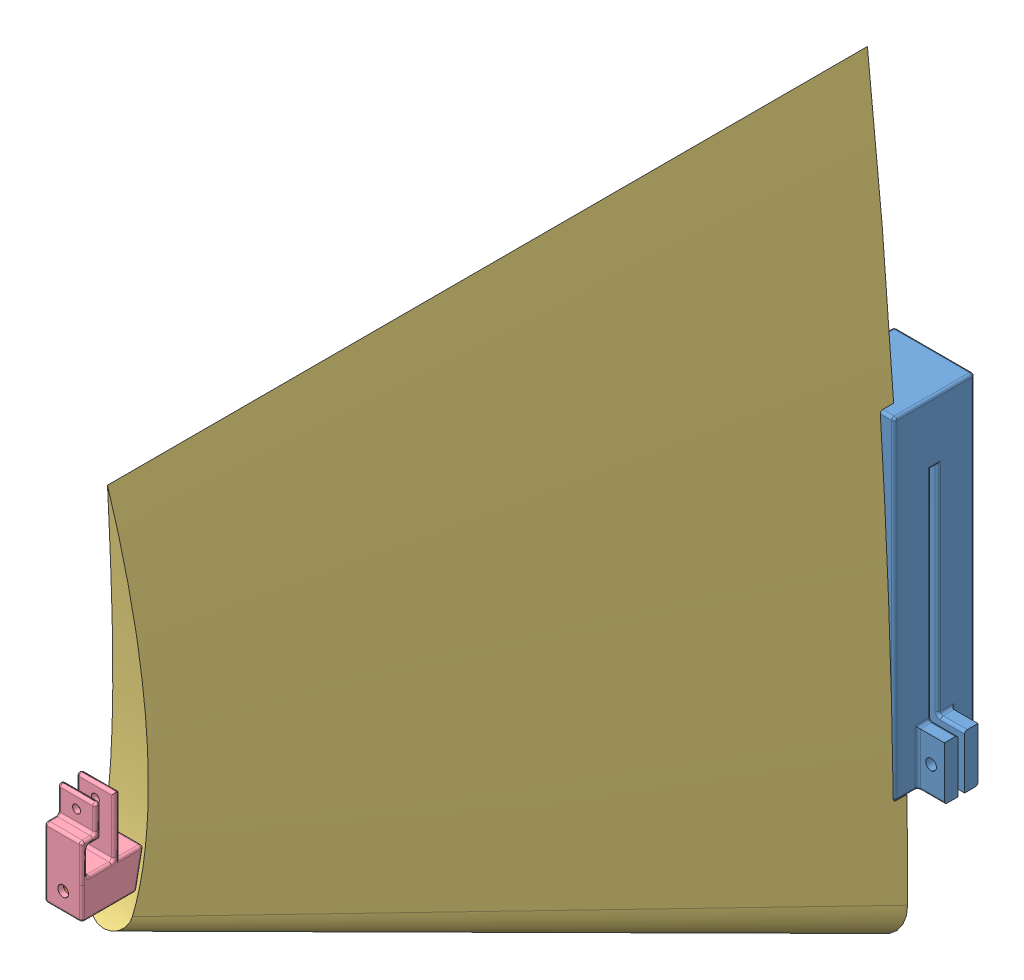
SolidWorks assembly vertical stabiliser, configuration Default. Lengths in mm.
Overall size (372.03 337.13 325.08).
23 component instances, 17 part files, 65 mates.
Components (placement in the parent):
- Tail Boom-1: Tail Boom [Default] at (20.2266 -517.2222 1.0272) size (20 1000 20) (hidden)
- Tail holder 1-1: Tail holder 1 [Default] at (31.2437 406.7778 -2.2179) x (1 0 0) z (0 -1 0) size (40 30 124) (hidden)
- tail holder 2-2: tail holder 2 [Default] at (21.0079 496.8403 300.9572) x (0 1 0) z (-1 0 0) size (10 323.08 10) (hidden)
- Tail Boom-2: Tail Boom [Default] at (-93.7734 -517.2222 1.0272) x (-1 0 0) z (0 0 -1) size (20 1000 20) (hidden)
- Tail holder 1-3: Tail holder 1 [Default] at (-104.7904 406.7778 4.2723) x (-1 0 0) z (0 -1 0) size (40 30 124)
- Vertical Stabilizer mk1-1: Vertical Stabilizer mk1 [Default] at (20.2266 346.1726 11.0272) x (-1 0 0) z (0 0 1) size (32.74 289.69 300.05) (hidden)
- tail holder 2-3: tail holder 2 [Default] at (-90.2109 492.4966 300.9572) x (1 0 0) z (0 1 0) size (10 323.08 10)
- Vertical Stabilizer mk1-2: Vertical Stabilizer mk1 [Default] at (-93.7734 346.1726 11.0272) x (-1 0 0) z (0 0 1) size (32.74 289.69 300.05)
- Horisontal stabiliser 11-1: Horisontal stabiliser 11 [Default] at (-336.7734 468.2778 304.1044) x (0 1 0) z (1 0 0) size (201.07 42.21 600) (hidden)
- top tail holder-1: top tail holder [Default] at (-94.9301 489.7185 257.1044) x (0 -1 0) z (-1 0 0) size (36 23 14)
- top tail holder-3: top tail holder [Default] at (19.0699 489.7185 257.1044) x (0 -1 0) z (-1 0 0) size (36 23 14) (hidden)
- Horizontal stabilizer bar-1: Horizontal stabilizer bar [Default] at (-336.7734 503.5632 301.2248) x (0 0 -1) z (1 0 0) size (10 10 600) (hidden)
- Tail motor mount A mk1-1: Tail motor mount A mk1 [Default] at (-97.9309 255.7778 2.925) x (1 0 0) z (0 -1 0) size (55 30 50) (hidden)
- Tail motor mount A mk1-2: Tail motor mount A mk1 [Default] at (24.3842 255.7778 -0.8707) x (-1 0 0) z (0 -1 0) size (55 30 50) (hidden)
- Rear motor crossbar-1: Rear motor crossbar [Default] at (-83.7734 228.9438 2.5044) x (0 1 0) z (1 0 0) size (20 20 94) (hidden)
- Tail motor mount B mk1-1: Tail motor mount B mk1 [Default] at (-38.3549 230.7778 31.0272) x (-1 0 0) z (0 -1 0) size (24 47 40) (hidden)
- Servo mk1-1: Servo mk1 [Default] at (-101.0589 247.0979 -13.9728) x (0.971449 -0.237248 0) z (0.237248 0.971449 0) size (33.6 12.5 34.08) (hidden)
- Flap mk1-1: Flap mk1 [Default] at (-35.9741 313.2778 -18.4266) x (0.996557 0 -0.082916) z (0 -1 0) size (2 40 165) (hidden)
- Servo arm mk1-1: Servo arm mk1 [Default] at (-114.6733 232.8778 17.976) x (-0.995872 0 0.090763) z (0 -1 0) size (10.8 29.4 3.1) (hidden)
- Servo hook mk1-1: Servo hook mk1 [Default] at (-40.7562 235.7778 -42.4932) x (-0.996557 0 0.082916) z (0.082916 0 0.996557) size (6 10 10) (hidden)
- Servo wire-1: Servo wire [Default] at (-102.5419 227.3778 -25.7684) x (-0.039777 0 0.999209) z (0 1 0) size (2 59.28 13) (hidden)
- Tail motor-1: Tail motor [Default] at (-36.7734 230.7778 31.0272) x (-0.55385 -0.832617 0) z (0 0 -1) size (27.5 27.5 31.35) (hidden)
- tail prop-1: tail prop [Default] at (-36.7734 230.7778 54.3772) x (0.926424 -0.376482 0) z (-0.376482 -0.926424 0) size (111.23 11.43 97.73) (hidden)
Mates (geometry in assembly coordinates):
- Distance4: distance = 94 mm anti-aligned: plane of Tail Boom-1 through (10.2266 482.7778 10.0272) normal (-1 0 0); plane of Tail Boom-2 through (-83.7734 482.7778 -7.9728) normal (1 0 0)
- Coincident27: coincident aligned: plane of Tail Boom-1 through (11.2266 482.7778 -8.9728) normal (0 0 -1); plane of Tail Boom-2 through (-84.7734 482.7778 -8.9728) normal (0 0 -1)
- Coincident59: coincident anti-aligned: plane of Tail Boom-2 through (-84.7734 482.7778 -8.9728) normal (0 0 -1); plane of Tail holder 1-3 through (-104.7904 381.7778 -8.9728) normal (0 0 1)
- Coincident60: coincident anti-aligned: plane of Tail Boom-2 through (-103.7734 482.7778 -7.9728) normal (-1 0 0); plane of Tail holder 1-3 through (-103.7734 381.7778 4.2723) normal (1 0 0)
- Parallel1: parallel anti-aligned: plane of Tail Boom-2 through (-83.7734 482.7778 -7.9728) normal (1 0 0); plane of Tail holder 1-3 through (-83.7734 381.7778 4.2723) normal (-1 0 0)
- Coincident63: coincident anti-aligned: plane of Tail Boom-2 through (-84.7734 482.7778 -7.9728) normal (0 1 0); plane of Tail holder 1-3 through (-104.7904 482.7778 4.2723) normal (0 -1 0)
- Coincident64: coincident anti-aligned: plane of Tail Boom-1 through (11.2266 482.7778 10.0272) normal (0 1 0); plane of Tail holder 1-1 through (31.2437 482.7778 -2.2179) normal (0 -1 0)
- Coincident65: coincident anti-aligned: plane of Tail Boom-1 through (10.2266 482.7778 10.0272) normal (-1 0 0); plane of Tail holder 1-1 through (10.2266 381.7778 -2.2179) normal (1 0 0)
- Coincident66: coincident anti-aligned: plane of Tail Boom-1 through (11.2266 482.7778 11.0272) normal (0 0 1); plane of Tail holder 1-1 through (31.2437 381.7778 11.0272) normal (0 0 -1)
- Coincident67: coincident anti-aligned: plane of Tail holder 1-1 through (31.2437 498.2778 110.0272) normal (0 -1 0); plane of tail holder 2-2 through (25.2266 498.2778 -9.0428) normal (0 1 0)
- Coincident68: coincident aligned: plane of Tail holder 1-1 through (31.2437 381.7778 -13.9728) normal (0 0 -1); plane of tail holder 2-2 through (16.2266 489.2778 -13.9728) normal (0 0 -1)
- Coincident69: coincident anti-aligned: plane of Tail holder 1-1 through (15.2266 406.7778 110.0272) normal (1 0 0); plane of tail holder 2-2 through (15.2266 488.2778 -9.0428) normal (-1 0 0)
- Coincident71: coincident aligned: plane of Tail holder 1-3 through (-104.7904 381.7778 -13.9728) normal (0 0 -1); plane of tail holder 2-3 through (-97.7734 497.2778 -13.9728) normal (0 0 -1)
- Coincident72: coincident anti-aligned: plane of Tail holder 1-3 through (-88.7734 406.7778 -107.9728) normal (-1 0 0); plane of tail holder 2-3 through (-88.7734 488.2778 -9.0428) normal (1 0 0)
- Coincident73: coincident anti-aligned: plane of Horisontal stabiliser 11-1 through (-336.7734 486.2778 267.1044) normal (0 1 0); plane of top tail holder-3 through (27.2266 486.2778 297.1044) normal (0 -1 0)
- Coincident74: coincident anti-aligned: plane of Horisontal stabiliser 11-1 through (27.2266 468.2778 267.1044) normal (-1 0 0); plane of top tail holder-3 through (27.2266 500.2778 297.1044) normal (1 0 0)
- Coincident75: coincident anti-aligned: plane of Horisontal stabiliser 11-1 through (-336.7734 468.2778 311.1044) normal (0 0 -1); plane of top tail holder-3 through (19.0699 489.7185 311.1044) normal (0 0 1)
- Coincident76: coincident anti-aligned: plane of Horisontal stabiliser 11-1 through (-100.7734 468.2778 267.1044) normal (1 0 0); plane of top tail holder-1 through (-100.7734 500.2778 297.1044) normal (-1 0 0)
- Coincident77: coincident anti-aligned: plane of Horisontal stabiliser 11-1 through (-336.7734 486.2778 267.1044) normal (0 1 0); plane of top tail holder-1 through (-86.7734 486.2778 297.1044) normal (0 -1 0)
- Coincident78: coincident anti-aligned: plane of Horisontal stabiliser 11-1 through (-336.7734 468.2778 311.1044) normal (0 0 -1); plane of top tail holder-1 through (-94.9301 489.7185 311.1044) normal (0 0 1)
- Coincident81: coincident anti-aligned: plane of Horisontal stabiliser 11-1 through (-390.7734 500.2778 304.1044) normal (0 1 0); plane of Horizontal stabilizer bar-1 through (263.2266 500.2778 309.1044) normal (0 -1 0)
- Coincident83: coincident anti-aligned: plane of Horisontal stabiliser 11-1 through (-390.7734 468.2778 309.1044) normal (0 0 -1); plane of Horizontal stabilizer bar-1 through (263.2266 510.2778 309.1044) normal (0 0 1)
- Coincident84: coincident aligned: plane of Horisontal stabiliser 11-1 through (263.2266 468.2778 304.1044) normal (1 0 0); plane of Horizontal stabilizer bar-1 through (263.2266 503.5632 301.2248) normal (1 0 0)
- Coincident86: coincident anti-aligned: plane of tail holder 2-3 through (-88.7734 488.2778 -9.0428) normal (1 0 0); plane of Vertical Stabilizer mk1-2 through (-88.7734 346.1726 321.0272) normal (-1 0 0)
- Coincident87: coincident anti-aligned: plane of tail holder 2-3 through (-98.7734 488.2778 -9.0428) normal (0 -1 0); plane of Vertical Stabilizer mk1-2 through (-93.7734 488.2778 321.0272) normal (0 1 0)
- Coincident89: coincident anti-aligned: plane of tail holder 2-2 through (25.2266 488.2778 -9.0428) normal (0 -1 0); plane of Vertical stabiliser 11-1 through (20.2266 488.2778 321.0272) normal (0 1 0)
- Coincident90: coincident anti-aligned: plane of tail holder 2-2 through (15.2266 488.2778 -9.0428) normal (-1 0 0); plane of Vertical stabiliser 11-1 through (15.2266 346.1726 321.0272) normal (1 0 0)
- Coincident91: coincident anti-aligned: plane of tail holder 2-2 through (25.2266 488.2778 -9.0428) normal (1 0 0); plane of top tail holder-3 through (25.2266 489.7185 257.1044) normal (-1 0 0)
- Coincident92: coincident anti-aligned: plane of tail holder 2-2 through (25.2266 488.2778 -9.0428) normal (0 -1 0); plane of top tail holder-3 through (19.0699 488.2778 257.1044) normal (0 1 0)
- Distance5: distance = 311.0772 mm: line of top tail holder-1 through (-87.7734 500.2778 297.1044) axis (-1 0 0); plane of tail holder 2-3 through (-97.7734 497.2778 -13.9728) normal (0 0 -1)
- Coincident93: coincident anti-aligned: plane of Tail Boom-1 through (11.2266 482.7778 11.0272) normal (0 0 1); plane of Vertical stabiliser 11-1 through (20.2266 346.1726 11.0272) normal (0 0 -1)
- Coincident94: coincident anti-aligned: plane of Tail Boom-2 through (-84.7734 482.7778 11.0272) normal (0 0 1); plane of Vertical Stabilizer mk1-2 through (-93.7734 346.1726 11.0272) normal (0 0 -1)
- Coincident95: coincident anti-aligned: plane of Tail Boom-2 through (-84.7734 482.7778 -8.9728) normal (0 0 -1); plane of Tail motor mount A mk1-1 through (-103.7734 205.7778 -8.9728) normal (0 0 1)
- Coincident96: coincident anti-aligned: plane of Tail Boom-2 through (-103.7734 482.7778 -7.9728) normal (-1 0 0); plane of Tail motor mount A mk1-1 through (-103.7734 205.7778 11.0272) normal (1 0 0)
- Distance6: distance = 126 mm anti-aligned: plane of Tail holder 1-3 through (-104.7904 381.7778 4.2723) normal (0 -1 0); plane of Tail motor mount A mk1-1 through (-97.9309 255.7778 2.925) normal (0 1 0)
- Coincident98: coincident anti-aligned: plane of Tail Boom-1 through (10.2266 482.7778 10.0272) normal (-1 0 0); plane of Tail motor mount A mk1-2 through (10.2266 205.7778 -8.9728) normal (1 0 0)
- Coincident99: coincident anti-aligned: plane of Tail Boom-1 through (11.2266 482.7778 -8.9728) normal (0 0 -1); plane of Tail motor mount A mk1-2 through (30.2266 205.7778 -8.9728) normal (0 0 1)
- Distance7: distance = 126 mm anti-aligned: plane of Tail holder 1-1 through (31.2437 381.7778 -2.2179) normal (0 -1 0); plane of Tail motor mount A mk1-2 through (24.3842 255.7778 -0.8707) normal (0 1 0)
- Coincident101: coincident anti-aligned: plane of Tail motor mount A mk1-1 through (-103.7734 205.7778 -8.9728) normal (0 0 1); plane of Rear motor crossbar-1 through (10.2266 220.7778 -8.9728) normal (0 0 -1)
- Coincident102: coincident anti-aligned: plane of Tail motor mount A mk1-1 through (-48.7734 240.7778 11.0272) normal (0 -1 0); plane of Rear motor crossbar-1 through (10.2266 240.7778 11.0272) normal (0 1 0)
- Coincident103: coincident anti-aligned: plane of Tail Boom-1 through (10.2266 482.7778 10.0272) normal (-1 0 0); plane of Rear motor crossbar-1 through (10.2266 228.9438 2.5044) normal (1 0 0)
- Coincident104: coincident anti-aligned: plane of Rear motor crossbar-1 through (10.2266 220.7778 -8.9728) normal (0 0 -1); plane of Tail motor mount B mk1-1 through (-9.7734 230.7778 -8.9728) normal (0 0 1)
- Coincident105: coincident anti-aligned: plane of Rear motor crossbar-1 through (10.2266 240.7778 11.0272) normal (0 1 0); plane of Tail motor mount B mk1-1 through (-9.7734 240.7778 31.0272) normal (0 -1 0)
- Distance8: distance = 15 mm anti-aligned: plane of Tail motor mount B mk1-1 through (-48.7734 230.7778 31.0272) normal (-1 0 0); plane of Tail motor mount A mk1-1 through (-63.7734 255.7778 2.925) normal (1 0 0)
- Width2: width anti-aligned: plane of Tail motor mount B mk1-1 through (-38.3549 215.7778 11.0272) normal (0 -1 0); plane of Flap mk1-1 through (-38.3549 245.7778 11.0272) normal (0 1 0); plane of Tail motor mount B mk1-1 through (-35.9741 313.2778 -18.4266) normal (0 1 0); plane of Flap mk1-1 through (-35.9741 148.2778 -18.4266) normal (0 -1 0)
- Coincident109: coincident anti-aligned: line of Tail motor mount B mk1-1 through (-36.7734 215.7778 -15.9728) axis (0 1 0); line of Flap mk1-1 through (-36.7734 313.2778 -15.9728) axis (0 -1 0)
- LimitAngle1: limit planar angle = 1.487785 rad anti-aligned: plane of Flap mk1-1 through (-37.7699 148.2778 -15.8899) normal (-0.996557 0 0.082916); plane of Tail motor mount B mk1-1 through (-9.7734 215.7778 -13.9728) normal (0 0 -1)
- Coincident111: coincident anti-aligned: plane of Tail motor mount A mk1-1 through (-108.7734 205.7778 -13.9728) normal (0 0 -1); plane of Servo mk1-1 through (-101.0589 247.0979 -13.9728) normal (0 0 1)
- Width3: width anti-aligned: plane of Servo mk1-1 through (-105.2734 260.1778 -26.4728) normal (-1 0 0); plane of Tail motor mount A mk1-1 through (-82.2734 260.1778 -26.4728) normal (1 0 0); plane of Servo mk1-1 through (-78.7734 205.7778 16.0272) normal (1 0 0); plane of Tail motor mount A mk1-1 through (-108.7734 205.7778 16.0272) normal (-1 0 0)
- Distance9: distance = 24 mm aligned: plane of Servo mk1-1 through (-101.0589 229.7778 -13.9728) normal (0 -1 0); plane of Tail motor mount A mk1-1 through (-97.9309 205.7778 2.925) normal (0 -1 0)
- Coincident114: coincident anti-aligned: cylinder of Servo mk1-1 through (-99.0234 229.7778 -20.2228) axis (0 1 0) radius 2.4; circle of Servo arm mk1-1
- Coincident115: coincident aligned: plane of Servo mk1-1 through (-101.0589 229.7778 -13.9728) normal (0 -1 0); plane of Servo arm mk1-1 through (-114.6733 229.7778 17.976) normal (0 -1 0)
- Coincident117: coincident anti-aligned: plane of Flap mk1-1 through (-37.7699 148.2778 -15.8899) normal (-0.996557 0 0.082916); plane of Servo hook mk1-1 through (-40.1231 225.7778 -44.1722) normal (0.996557 0 -0.082916)
- Width5: width aligned: plane of Servo hook mk1-1 through (-40.7562 225.7778 -42.4932) normal (0 -1 0); plane of Flap mk1-1 through (-40.7562 235.7778 -42.4932) normal (0 1 0); plane of Servo hook mk1-1 through (-35.9741 148.2778 -18.4266) normal (0 -1 0); plane of Flap mk1-1 through (-35.9741 313.2778 -18.4266) normal (0 1 0)
- Distance12: distance = 11.62 mm aligned: plane of Servo hook mk1-1 through (-40.1231 225.7778 -44.1722) normal (-0.082916 0 -0.996557); plane of Flap mk1-1 through (-41.0866 148.2778 -55.7522) normal (-0.082916 0 -0.996557)
- LimitAngle3: limit planar angle = 1.661685 rad anti-aligned: plane of Servo arm mk1-1 through (-120.1754 229.7778 -42.3945) normal (-0.090763 0 -0.995872); plane of Tail motor mount A mk1-1 through (-108.7734 205.7778 16.0272) normal (-1 0 0)
- Concentric2: concentric aligned: cylinder of Servo arm mk1-1 through (-100.9294 229.7778 -41.1362) axis (0 1 0) radius 1; cylinder of Servo wire-1 through (-100.9294 219.8778 -41.1362) axis (0 1 0) radius 1
- Concentric3: concentric anti-aligned: cylinder of Servo hook mk1-1 through (-43.6947 244.7778 -38.8577) axis (0 -1 0) radius 1; cylinder of Servo wire-1 through (-43.6947 168.0978 -38.8577) axis (0 1 0) radius 1
- Coincident122: coincident aligned: plane of Servo arm mk1-1 through (-114.6733 232.8778 17.976) normal (0 1 0); plane of Servo wire-1 through (-100.9294 232.8778 -41.1362) normal (0 1 0)
- Coincident123: coincident anti-aligned: plane of Tail holder 1-3 through (-104.7904 488.2778 -107.9728) normal (0 1 0); plane of tail holder 2-3 through (-98.7734 488.2778 -9.0428) normal (0 -1 0)
- Coincident125: coincident anti-aligned: plane of Tail motor mount A mk1-2 through (-24.7734 240.7778 -8.9728) normal (0 -1 0); plane of Rear motor crossbar-1 through (10.2266 240.7778 11.0272) normal (0 1 0)
- Concentric13: concentric aligned: cylinder of Tail motor mount B mk1-1 through (-36.7734 230.7778 26.0272) axis (0 0 1) radius 11; cylinder of Tail motor-1 through (-36.7734 230.7778 62.3772) axis (0 0 1) radius 13.75
- Coincident126: coincident anti-aligned: plane of Tail motor mount B mk1-1 through (-38.3549 230.7778 31.0272) normal (0 0 1); plane of Tail motor-1 through (-36.7734 230.7778 31.0272) normal (0 0 -1)
- Concentric14: concentric anti-aligned: cylinder of Tail motor-1 through (-36.7734 230.7778 62.3772) axis (0 0 1) radius 2.5; cylinder of tail prop-1 through (-36.7734 230.7778 62.3772) axis (0 0 -1) radius 2.5
- Coincident127: coincident aligned: plane of Tail motor-1 through (-38.158 228.6963 62.3772) normal (0 0 1); plane of tail prop-1 through (-36.7734 230.7778 62.3772) normal (0 0 1)
